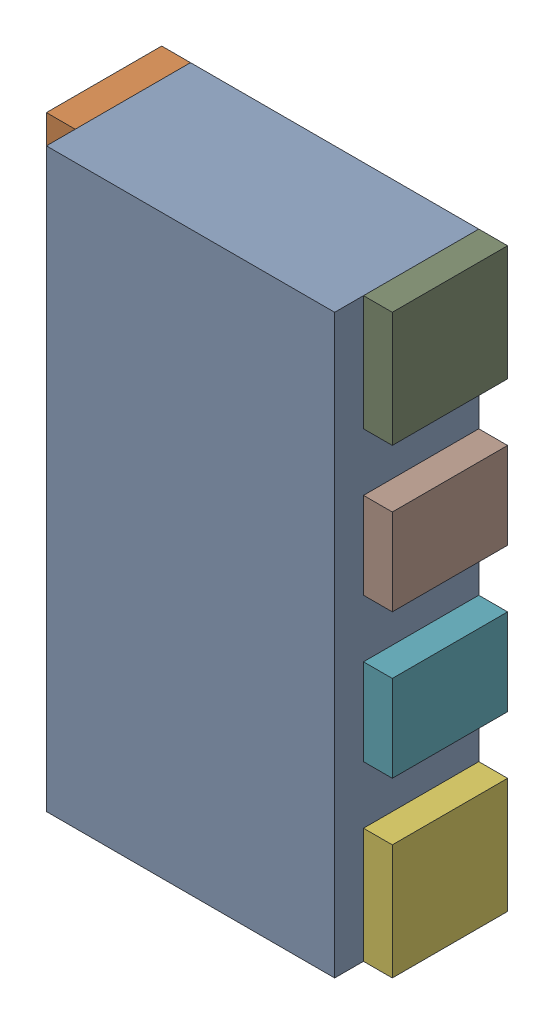
SolidWorks assembly RN1, configuration Default. Lengths in mm.
Overall size (1.2 2 0.5).
18 component instances, 3 part files, 0 mates.
Components (placement in the parent):
- 836750320-1: 836750320 [Default] at (124.25 11.2 0) size (1 2 0.5)
  - Extruded_15-1: Extruded_15 [Default] at origin size (1 2 0.5)
- 791587232-1: 791587232 [Default] at (123.7 12 0) size (0.1 0.4 0.4)
  - Extruded_10-1: Extruded_10 [Default] at origin size (0.1 0.4 0.4)
- 836750576-1: 836750576 [Default] at (123.7 11.45 0) size (0.1 0.3 0.4)
  - Extruded_14-1: Extruded_14 [Default] at origin size (0.1 0.3 0.4)
- 836750576-2: 836750576 [Default] at (123.7 10.95 0) size (0.1 0.3 0.4)
  - Extruded_14-1: Extruded_14 [Default] at origin size (0.1 0.3 0.4)
- 791587232-2: 791587232 [Default] at (123.7 10.4 0) size (0.1 0.4 0.4)
  - Extruded_10-1: Extruded_10 [Default] at origin size (0.1 0.4 0.4)
- 791587232-3: 791587232 [Default] at (124.8 10.4 0) size (0.1 0.4 0.4)
  - Extruded_10-1: Extruded_10 [Default] at origin size (0.1 0.4 0.4)
- 836750576-3: 836750576 [Default] at (124.8 10.95 0) size (0.1 0.3 0.4)
  - Extruded_14-1: Extruded_14 [Default] at origin size (0.1 0.3 0.4)
- 836750576-4: 836750576 [Default] at (124.8 11.45 0) size (0.1 0.3 0.4)
  - Extruded_14-1: Extruded_14 [Default] at origin size (0.1 0.3 0.4)
- 791587232-4: 791587232 [Default] at (124.8 12 0) size (0.1 0.4 0.4)
  - Extruded_10-1: Extruded_10 [Default] at origin size (0.1 0.4 0.4)
